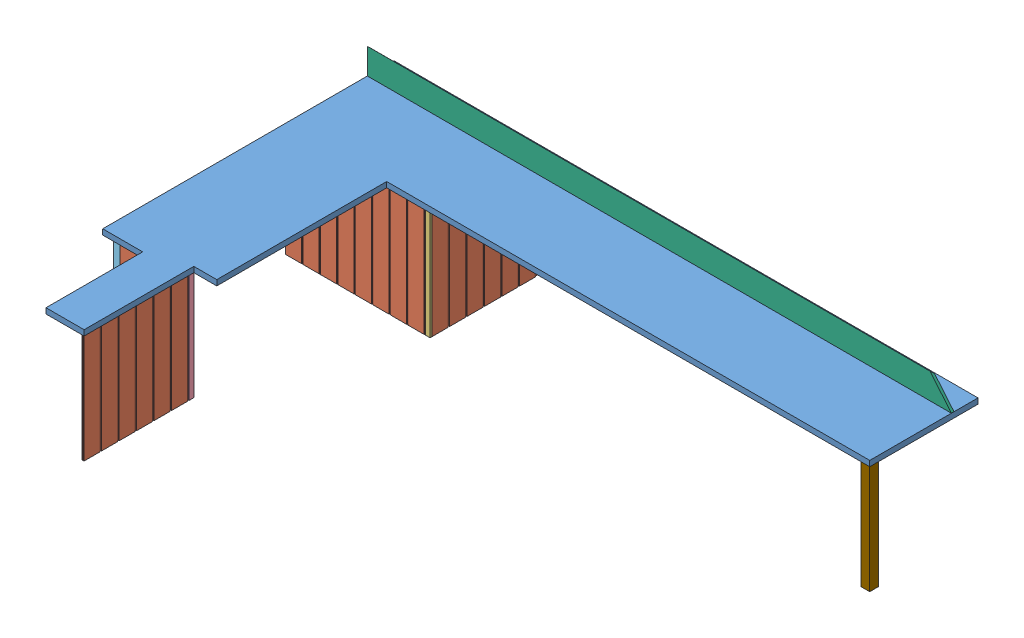
SolidWorks assembly Brüstung-Arbeit, configuration Standard. Lengths in mm.
Overall size (4046.49 966.32 2687.4).
32 component instances, 9 part files, 94 mates.
Components (placement in the parent):
- Werkplatte-1: Werkplatte [Standard] at (-2563.2532 392.3163 2702.7833) size (4046.49 38 2687.4)
- Schalbrett-1: Schalbrett [Standard] at (-2381.7532 392.3163 3445.7833) x (1 0 0) z (0 0 -1) size (131 750 14)
- Schalbrett-2: Schalbrett [Standard] at (-2260.7532 392.3163 3445.7833) x (1 0 0) z (0 0 -1) size (131 750 14)
- Schalbrett-3: Schalbrett [Standard] at (-2139.7532 392.3163 3445.7833) x (1 0 0) z (0 0 -1) size (131 750 14)
- Schalbrett-4: Schalbrett [Standard] at (-2018.7532 392.3163 3445.7833) x (1 0 0) z (0 0 -1) size (131 750 14)
- Schalbrett-5: Schalbrett [Standard] at (-1897.7532 392.3163 3445.7833) x (1 0 0) z (0 0 -1) size (131 750 14)
- Schalbrett-6: Schalbrett [Standard] at (-1776.7532 392.3163 3445.7833) x (1 0 0) z (0 0 -1) size (131 750 14)
- Schalbrett-7: Schalbrett [Standard] at (-1655.7532 392.3163 3445.7833) x (1 0 0) z (0 0 -1) size (131 750 14)
- Schalbrett-15: Schalbrett [Standard] at (-2502.7532 392.3163 3445.7833) x (1 0 0) z (0 0 -1) size (131 750 14)
- Schalbrett-Ecke1-1: Schalbrett-Ecke1 [Standard] at (-1534.7532 392.3163 3445.7833) x (1 0 0) z (0 0 -1) size (32 750 14)
- Schalbrett-9: Schalbrett [Standard] at (-1570.2532 392.3163 3378.2833) x (0 0 -1) z (-1 0 0) size (131 750 14)
- Schalbrett-10: Schalbrett [Standard] at (-1570.2532 392.3163 3257.2833) x (0 0 -1) z (-1 0 0) size (131 750 14)
- Schalbrett-11: Schalbrett [Standard] at (-1570.2532 392.3163 3136.2833) x (0 0 -1) z (-1 0 0) size (131 750 14)
- Schalbrett-12: Schalbrett [Standard] at (-1570.2532 392.3163 3015.2833) x (0 0 -1) z (-1 0 0) size (131 750 14)
- Schalbrett-13: Schalbrett [Standard] at (-1570.2532 392.3163 2894.2833) x (0 0 -1) z (-1 0 0) size (131 750 14)
- Schalbrett-14: Schalbrett [Standard] at (-1570.2532 392.3163 2773.2833) x (0 0 -1) z (-1 0 0) size (131 750 14)
- Schalbrett-16: Schalbrett [Standard] at (-2029.2532 392.3163 5329.6883) x (0 0 -1) z (-1 0 0) size (131 750 14)
- Schalbrett-17: Schalbrett [Standard] at (-2029.2532 392.3163 5208.6883) x (0 0 -1) z (-1 0 0) size (131 750 14)
- Schalbrett-18: Schalbrett [Standard] at (-2029.2532 392.3163 5087.6883) x (0 0 -1) z (-1 0 0) size (131 750 14)
- Schalbrett-19: Schalbrett [Standard] at (-2029.2532 392.3163 4966.6883) x (0 0 -1) z (-1 0 0) size (131 750 14)
- Schalbrett-20: Schalbrett [Standard] at (-2029.2532 392.3163 4845.6883) x (0 0 -1) z (-1 0 0) size (131 750 14)
- Schalbrett-21: Schalbrett [Standard] at (-2029.2532 392.3163 4724.6883) x (0 0 -1) z (-1 0 0) size (131 750 14)
- Schalbrett-23: Schalbrett [Standard] at (-2096.7532 392.3163 4637.1883) x (-1 0 0) z (0 0 1) size (131 750 14)
- Schalbrett-24: Schalbrett [Standard] at (-2217.7532 392.3163 4637.1883) x (-1 0 0) z (0 0 1) size (131 750 14)
- Schalbrett-25: Schalbrett [Standard] at (-2338.7532 392.3163 4637.1883) x (-1 0 0) z (0 0 1) size (131 750 14)
- Schalbrett-26: Schalbrett [Standard] at (-2459.7532 392.3163 4637.1883) x (-1 0 0) z (0 0 1) size (131 750 14)
- Schalbrett-Ecke2-1: Schalbrett-Ecke2 [Standard] at (-2029.2532 392.3163 4603.6883) x (0 0 -1) z (-1 0 0) size (34 750 14)
- Schalbrett-Ecke3-1: Schalbrett-Ecke3 [Standard] at (-2580.7532 392.3163 4637.1883) x (-1 0 0) z (0 0 1) size (43 750 14)
- Steckdosenleiste-1: Steckdosenleiste [Standard] at (-540.0103 519.4748 2868.9113) size (4046.49 178.32 18)
- Tunnel-Unten-1: Tunnel-Unten [Standard] at (-2488.2532 242.3163 4041.4883) x (0 0 -1) z (1 0 0) size (1177.4 18 150)
- Tunnel-Vorn-1: Tunnel-Vorn [Standard] at (-2431.2532 326.3163 4041.4883) x (0 0 -1) z (1 0 0) size (1177.4 132 18)
- Bein-1: Bein [Standard] at (1453.2326 -357.6837 3422.7833) size (60 750 60)
Mates (geometry in assembly coordinates):
- Deckungsgleich1: coincident anti-aligned: plane of Werkplatte-1 through (-2563.2532 392.3163 2702.7833) normal (0 -1 0); plane of Schalbrett-15 through (-2453.2532 392.3163 3448.7833) normal (0 1 0)
- Deckungsgleich2: coincident anti-aligned: plane of Werkplatte-1 through (-2563.2532 392.3163 2702.7833) normal (0 -1 0); plane of Schalbrett-1 through (-2332.2532 392.3163 3448.7833) normal (0 1 0)
- Deckungsgleich3: coincident anti-aligned: plane of Werkplatte-1 through (-2563.2532 392.3163 2702.7833) normal (0 -1 0); plane of Schalbrett-2 through (-2211.2532 392.3163 3448.7833) normal (0 1 0)
- Deckungsgleich4: coincident anti-aligned: plane of Werkplatte-1 through (-2563.2532 392.3163 2702.7833) normal (0 -1 0); plane of Schalbrett-3 through (-2090.2532 392.3163 3448.7833) normal (0 1 0)
- Deckungsgleich5: coincident anti-aligned: plane of Werkplatte-1 through (-2563.2532 392.3163 2702.7833) normal (0 -1 0); plane of Schalbrett-4 through (-1969.2532 392.3163 3448.7833) normal (0 1 0)
- Deckungsgleich6: coincident anti-aligned: plane of Werkplatte-1 through (-2563.2532 392.3163 2702.7833) normal (0 -1 0); plane of Schalbrett-5 through (-1848.2532 392.3163 3448.7833) normal (0 1 0)
- Deckungsgleich7: coincident anti-aligned: plane of Werkplatte-1 through (-2563.2532 392.3163 2702.7833) normal (0 -1 0); plane of Schalbrett-6 through (-1727.2532 392.3163 3448.7833) normal (0 1 0)
- Deckungsgleich8: coincident anti-aligned: plane of Werkplatte-1 through (-2563.2532 392.3163 2702.7833) normal (0 -1 0); plane of Schalbrett-7 through (-1606.2532 392.3163 3448.7833) normal (0 1 0)
- Deckungsgleich10: coincident aligned: plane of Werkplatte-1 through (-2563.2532 430.3163 4630.1883) normal (-1 0 0); plane of Schalbrett-15 through (-2563.2532 -357.6837 3447.7833) normal (-1 0 0)
- Deckungsgleich11: coincident anti-aligned: plane of Schalbrett-1 through (-2432.2532 -357.6837 3447.7833) normal (0 0 -1); plane of Schalbrett-15 through (-2442.2532 -357.6837 3447.7833) normal (0 0 1)
- Deckungsgleich12: coincident anti-aligned: plane of Schalbrett-1 through (-2321.2532 -357.6837 3447.7833) normal (0 0 1); plane of Schalbrett-2 through (-2311.2532 -357.6837 3447.7833) normal (0 0 -1)
- Deckungsgleich13: coincident anti-aligned: plane of Schalbrett-2 through (-2200.2532 -357.6837 3447.7833) normal (0 0 1); plane of Schalbrett-3 through (-2190.2532 -357.6837 3447.7833) normal (0 0 -1)
- Deckungsgleich14: coincident anti-aligned: plane of Schalbrett-3 through (-2079.2532 -357.6837 3447.7833) normal (0 0 1); plane of Schalbrett-4 through (-2069.2532 -357.6837 3447.7833) normal (0 0 -1)
- Deckungsgleich15: coincident anti-aligned: plane of Schalbrett-4 through (-1958.2532 -357.6837 3447.7833) normal (0 0 1); plane of Schalbrett-5 through (-1948.2532 -357.6837 3447.7833) normal (0 0 -1)
- Deckungsgleich16: coincident anti-aligned: plane of Schalbrett-5 through (-1837.2532 -357.6837 3447.7833) normal (0 0 1); plane of Schalbrett-6 through (-1827.2532 -357.6837 3447.7833) normal (0 0 -1)
- Deckungsgleich17: coincident anti-aligned: plane of Schalbrett-6 through (-1716.2532 -357.6837 3447.7833) normal (0 0 1); plane of Schalbrett-7 through (-1706.2532 -357.6837 3447.7833) normal (0 0 -1)
- Deckungsgleich19: coincident aligned: plane of Werkplatte-1 through (-1863.2532 430.3163 3452.7833) normal (0 0 1); plane of Schalbrett-15 through (-2453.2532 -357.6837 3452.7833) normal (0 0 1)
- Deckungsgleich20: coincident anti-aligned: plane of Schalbrett-1 through (-2432.2532 -357.6837 3443.7833) normal (-1 0 0); plane of Schalbrett-15 through (-2432.2532 -357.6837 3447.7833) normal (1 0 0)
- Deckungsgleich21: coincident anti-aligned: plane of Schalbrett-1 through (-2311.2532 -357.6837 3447.7833) normal (1 0 0); plane of Schalbrett-2 through (-2311.2532 -357.6837 3443.7833) normal (-1 0 0)
- Deckungsgleich22: coincident anti-aligned: plane of Schalbrett-2 through (-2190.2532 -357.6837 3447.7833) normal (1 0 0); plane of Schalbrett-3 through (-2190.2532 -357.6837 3443.7833) normal (-1 0 0)
- Deckungsgleich23: coincident anti-aligned: plane of Schalbrett-3 through (-2069.2532 -357.6837 3447.7833) normal (1 0 0); plane of Schalbrett-4 through (-2069.2532 -357.6837 3443.7833) normal (-1 0 0)
- Deckungsgleich24: coincident anti-aligned: plane of Schalbrett-4 through (-1948.2532 -357.6837 3447.7833) normal (1 0 0); plane of Schalbrett-5 through (-1948.2532 -357.6837 3443.7833) normal (-1 0 0)
- Deckungsgleich25: coincident anti-aligned: plane of Schalbrett-5 through (-1827.2532 -357.6837 3447.7833) normal (1 0 0); plane of Schalbrett-6 through (-1827.2532 -357.6837 3443.7833) normal (-1 0 0)
- Deckungsgleich26: coincident anti-aligned: plane of Schalbrett-6 through (-1706.2532 -357.6837 3447.7833) normal (1 0 0); plane of Schalbrett-7 through (-1706.2532 -357.6837 3443.7833) normal (-1 0 0)
- Deckungsgleich28: coincident anti-aligned: plane of Werkplatte-1 through (-2563.2532 392.3163 2702.7833) normal (0 -1 0); plane of Schalbrett-Ecke1-1 through (-1485.2532 392.3163 3448.7833) normal (0 1 0)
- Deckungsgleich29: coincident anti-aligned: plane of Schalbrett-7 through (-1595.2532 -357.6837 3447.7833) normal (0 0 1); plane of Schalbrett-Ecke1-1 through (-1585.2532 -357.6837 3447.7833) normal (0 0 -1)
- Deckungsgleich30: coincident anti-aligned: plane of Schalbrett-7 through (-1585.2532 -357.6837 3447.7833) normal (1 0 0); plane of Schalbrett-Ecke1-1 through (-1585.2532 -357.6837 3443.7833) normal (-1 0 0)
- Deckungsgleich31: coincident anti-aligned: plane of Werkplatte-1 through (-2563.2532 392.3163 2702.7833) normal (0 -1 0); plane of Schalbrett-9 through (-1567.2532 392.3163 3328.7833) normal (0 1 0)
- Deckungsgleich32: coincident anti-aligned: plane of Werkplatte-1 through (-2563.2532 392.3163 2702.7833) normal (0 -1 0); plane of Schalbrett-10 through (-1567.2532 392.3163 3207.7833) normal (0 1 0)
- Deckungsgleich33: coincident anti-aligned: plane of Werkplatte-1 through (-2563.2532 392.3163 2702.7833) normal (0 -1 0); plane of Schalbrett-11 through (-1567.2532 392.3163 3086.7833) normal (0 1 0)
- Deckungsgleich34: coincident anti-aligned: plane of Werkplatte-1 through (-2563.2532 392.3163 2702.7833) normal (0 -1 0); plane of Schalbrett-12 through (-1567.2532 392.3163 2965.7833) normal (0 1 0)
- Deckungsgleich35: coincident anti-aligned: plane of Werkplatte-1 through (-2563.2532 392.3163 2702.7833) normal (0 -1 0); plane of Schalbrett-13 through (-1567.2532 392.3163 2844.7833) normal (0 1 0)
- Deckungsgleich36: coincident anti-aligned: plane of Werkplatte-1 through (-2563.2532 392.3163 2702.7833) normal (0 -1 0); plane of Schalbrett-14 through (-1567.2532 392.3163 2723.7833) normal (0 1 0)
- Deckungsgleich37: coincident anti-aligned: plane of Schalbrett-Ecke1-1 through (-1474.2532 -357.6837 3438.7833) normal (0 0 -1); plane of Schalbrett-9 through (-1568.2532 -357.6837 3438.7833) normal (0 0 1)
- Deckungsgleich38: coincident aligned: plane of Schalbrett-Ecke1-1 through (-1563.2532 642.3163 3438.7833) normal (1 0 0); plane of Schalbrett-9 through (-1563.2532 -357.6837 3328.7833) normal (1 0 0)
- Deckungsgleich39: coincident anti-aligned: plane of Schalbrett-9 through (-1568.2532 -357.6837 3317.7833) normal (1 0 0); plane of Schalbrett-10 through (-1568.2532 -357.6837 3307.7833) normal (-1 0 0)
- Deckungsgleich40: coincident anti-aligned: plane of Schalbrett-10 through (-1568.2532 -357.6837 3196.7833) normal (1 0 0); plane of Schalbrett-11 through (-1568.2532 -357.6837 3186.7833) normal (-1 0 0)
- Deckungsgleich41: coincident anti-aligned: plane of Schalbrett-11 through (-1568.2532 -357.6837 3075.7833) normal (1 0 0); plane of Schalbrett-12 through (-1568.2532 -357.6837 3065.7833) normal (-1 0 0)
- Deckungsgleich42: coincident anti-aligned: plane of Schalbrett-12 through (-1568.2532 -357.6837 2954.7833) normal (1 0 0); plane of Schalbrett-13 through (-1568.2532 -357.6837 2944.7833) normal (-1 0 0)
- Deckungsgleich43: coincident anti-aligned: plane of Schalbrett-13 through (-1568.2532 -357.6837 2833.7833) normal (1 0 0); plane of Schalbrett-14 through (-1568.2532 -357.6837 2823.7833) normal (-1 0 0)
- Deckungsgleich44: coincident anti-aligned: plane of Schalbrett-9 through (-1568.2532 -357.6837 3307.7833) normal (0 0 -1); plane of Schalbrett-10 through (-1572.2532 -357.6837 3307.7833) normal (0 0 1)
- Deckungsgleich45: coincident anti-aligned: plane of Schalbrett-10 through (-1568.2532 -357.6837 3186.7833) normal (0 0 -1); plane of Schalbrett-11 through (-1572.2532 -357.6837 3186.7833) normal (0 0 1)
- Deckungsgleich46: coincident anti-aligned: plane of Schalbrett-11 through (-1568.2532 -357.6837 3065.7833) normal (0 0 -1); plane of Schalbrett-12 through (-1572.2532 -357.6837 3065.7833) normal (0 0 1)
- Deckungsgleich47: coincident anti-aligned: plane of Schalbrett-12 through (-1568.2532 -357.6837 2944.7833) normal (0 0 -1); plane of Schalbrett-13 through (-1572.2532 -357.6837 2944.7833) normal (0 0 1)
- Deckungsgleich48: coincident anti-aligned: plane of Schalbrett-13 through (-1568.2532 -357.6837 2823.7833) normal (0 0 -1); plane of Schalbrett-14 through (-1572.2532 -357.6837 2823.7833) normal (0 0 1)
- Deckungsgleich49: coincident anti-aligned: plane of Werkplatte-1 through (-2563.2532 392.3163 2702.7833) normal (0 -1 0); plane of Schalbrett-16 through (-2026.2532 392.3163 5280.1883) normal (0 1 0)
- Deckungsgleich50: coincident anti-aligned: plane of Werkplatte-1 through (-2563.2532 392.3163 2702.7833) normal (0 -1 0); plane of Schalbrett-17 through (-2026.2532 392.3163 5159.1883) normal (0 1 0)
- Deckungsgleich51: coincident anti-aligned: plane of Werkplatte-1 through (-2563.2532 392.3163 2702.7833) normal (0 -1 0); plane of Schalbrett-18 through (-2026.2532 392.3163 5038.1883) normal (0 1 0)
- Deckungsgleich52: coincident anti-aligned: plane of Werkplatte-1 through (-2563.2532 392.3163 2702.7833) normal (0 -1 0); plane of Schalbrett-19 through (-2026.2532 392.3163 4917.1883) normal (0 1 0)
- Deckungsgleich53: coincident anti-aligned: plane of Werkplatte-1 through (-2563.2532 392.3163 2702.7833) normal (0 -1 0); plane of Schalbrett-20 through (-2026.2532 392.3163 4796.1883) normal (0 1 0)
- Deckungsgleich54: coincident anti-aligned: plane of Werkplatte-1 through (-2563.2532 392.3163 2702.7833) normal (0 -1 0); plane of Schalbrett-21 through (-2026.2532 392.3163 4675.1883) normal (0 1 0)
- Deckungsgleich56: coincident anti-aligned: plane of Werkplatte-1 through (-2563.2532 392.3163 2702.7833) normal (0 -1 0); plane of Schalbrett-23 through (-2146.2532 392.3163 4634.1883) normal (0 1 0)
- Deckungsgleich57: coincident anti-aligned: plane of Werkplatte-1 through (-2563.2532 392.3163 2702.7833) normal (0 -1 0); plane of Schalbrett-24 through (-2267.2532 392.3163 4634.1883) normal (0 1 0)
- Deckungsgleich58: coincident anti-aligned: plane of Werkplatte-1 through (-2563.2532 392.3163 2702.7833) normal (0 -1 0); plane of Schalbrett-25 through (-2388.2532 392.3163 4634.1883) normal (0 1 0)
- Deckungsgleich59: coincident anti-aligned: plane of Werkplatte-1 through (-2563.2532 392.3163 2702.7833) normal (0 -1 0); plane of Schalbrett-26 through (-2509.2532 392.3163 4634.1883) normal (0 1 0)
- Deckungsgleich61: coincident aligned: plane of Werkplatte-1 through (-2022.2532 430.3163 5390.1883) normal (0 0 1); plane of Schalbrett-16 through (-2027.2532 -357.6837 5390.1883) normal (0 0 1)
- Deckungsgleich62: coincident aligned: plane of Werkplatte-1 through (-2022.2532 430.3163 5390.1883) normal (1 0 0); plane of Schalbrett-16 through (-2022.2532 -357.6837 5280.1883) normal (1 0 0)
- Deckungsgleich63: coincident anti-aligned: plane of Schalbrett-16 through (-2027.2532 -357.6837 5269.1883) normal (1 0 0); plane of Schalbrett-17 through (-2027.2532 -357.6837 5259.1883) normal (-1 0 0)
- Deckungsgleich64: coincident anti-aligned: plane of Schalbrett-17 through (-2027.2532 -357.6837 5148.1883) normal (1 0 0); plane of Schalbrett-18 through (-2027.2532 -357.6837 5138.1883) normal (-1 0 0)
- Deckungsgleich65: coincident anti-aligned: plane of Schalbrett-18 through (-2027.2532 -357.6837 5027.1883) normal (1 0 0); plane of Schalbrett-19 through (-2027.2532 -357.6837 5017.1883) normal (-1 0 0)
- Deckungsgleich66: coincident anti-aligned: plane of Schalbrett-19 through (-2027.2532 -357.6837 4906.1883) normal (1 0 0); plane of Schalbrett-20 through (-2027.2532 -357.6837 4896.1883) normal (-1 0 0)
- Deckungsgleich67: coincident anti-aligned: plane of Schalbrett-20 through (-2027.2532 -357.6837 4785.1883) normal (1 0 0); plane of Schalbrett-21 through (-2027.2532 -357.6837 4775.1883) normal (-1 0 0)
- Deckungsgleich69: coincident anti-aligned: plane of Schalbrett-16 through (-2027.2532 -357.6837 5259.1883) normal (0 0 -1); plane of Schalbrett-17 through (-2031.2532 -357.6837 5259.1883) normal (0 0 1)
- Deckungsgleich70: coincident anti-aligned: plane of Schalbrett-17 through (-2027.2532 -357.6837 5138.1883) normal (0 0 -1); plane of Schalbrett-18 through (-2031.2532 -357.6837 5138.1883) normal (0 0 1)
- Deckungsgleich71: coincident anti-aligned: plane of Schalbrett-18 through (-2027.2532 -357.6837 5017.1883) normal (0 0 -1); plane of Schalbrett-19 through (-2031.2532 -357.6837 5017.1883) normal (0 0 1)
- Deckungsgleich72: coincident anti-aligned: plane of Schalbrett-19 through (-2027.2532 -357.6837 4896.1883) normal (0 0 -1); plane of Schalbrett-20 through (-2031.2532 -357.6837 4896.1883) normal (0 0 1)
- Deckungsgleich73: coincident anti-aligned: plane of Schalbrett-20 through (-2027.2532 -357.6837 4775.1883) normal (0 0 -1); plane of Schalbrett-21 through (-2031.2532 -357.6837 4775.1883) normal (0 0 1)
- Deckungsgleich75: coincident anti-aligned: plane of Werkplatte-1 through (-2563.2532 392.3163 2702.7833) normal (0 -1 0); plane of Schalbrett-Ecke2-1 through (-2026.2532 392.3163 4554.1883) normal (0 1 0)
- Deckungsgleich76: coincident anti-aligned: plane of Schalbrett-21 through (-2027.2532 -357.6837 4664.1883) normal (1 0 0); plane of Schalbrett-Ecke2-1 through (-2027.2532 -357.6837 4654.1883) normal (-1 0 0)
- Deckungsgleich77: coincident anti-aligned: plane of Schalbrett-21 through (-2027.2532 -357.6837 4654.1883) normal (0 0 -1); plane of Schalbrett-Ecke2-1 through (-2031.2532 -357.6837 4654.1883) normal (0 0 1)
- Deckungsgleich78: coincident anti-aligned: plane of Werkplatte-1 through (-2563.2532 392.3163 2702.7833) normal (0 -1 0); plane of Schalbrett-23 through (-2146.2532 392.3163 4634.1883) normal (0 1 0)
- Deckungsgleich79: coincident anti-aligned: plane of Schalbrett-23 through (-2036.2532 -357.6837 4644.1883) normal (1 0 0); plane of Schalbrett-Ecke2-1 through (-2036.2532 -357.6837 4543.1883) normal (-1 0 0)
- Deckungsgleich80: coincident aligned: plane of Schalbrett-23 through (-2146.2532 -357.6837 4630.1883) normal (0 0 -1); plane of Schalbrett-Ecke2-1 through (-2022.2532 -607.6837 4630.1883) normal (0 0 -1)
- Deckungsgleich81: coincident anti-aligned: plane of Schalbrett-23 through (-2157.2532 -357.6837 4635.1883) normal (0 0 -1); plane of Schalbrett-24 through (-2167.2532 -357.6837 4635.1883) normal (0 0 1)
- Deckungsgleich82: coincident anti-aligned: plane of Schalbrett-23 through (-2167.2532 -357.6837 4635.1883) normal (-1 0 0); plane of Schalbrett-24 through (-2167.2532 -357.6837 4639.1883) normal (1 0 0)
- Deckungsgleich83: coincident anti-aligned: plane of Schalbrett-24 through (-2278.2532 -357.6837 4635.1883) normal (0 0 -1); plane of Schalbrett-25 through (-2288.2532 -357.6837 4635.1883) normal (0 0 1)
- Deckungsgleich85: coincident anti-aligned: plane of Schalbrett-24 through (-2288.2532 -357.6837 4635.1883) normal (-1 0 0); plane of Schalbrett-25 through (-2288.2532 -357.6837 4639.1883) normal (1 0 0)
- Deckungsgleich86: coincident anti-aligned: plane of Schalbrett-25 through (-2409.2532 -357.6837 4635.1883) normal (-1 0 0); plane of Schalbrett-26 through (-2409.2532 -357.6837 4639.1883) normal (1 0 0)
- Deckungsgleich87: coincident anti-aligned: plane of Schalbrett-25 through (-2399.2532 -357.6837 4635.1883) normal (0 0 -1); plane of Schalbrett-26 through (-2409.2532 -357.6837 4635.1883) normal (0 0 1)
- Deckungsgleich93: coincident anti-aligned: plane of Schalbrett-26 through (-2530.2532 -357.6837 4635.1883) normal (-1 0 0); plane of Schalbrett-Ecke3-1 through (-2530.2532 -357.6837 4639.1883) normal (1 0 0)
- Deckungsgleich94: coincident anti-aligned: plane of Werkplatte-1 through (-2563.2532 392.3163 2702.7833) normal (0 -1 0); plane of Schalbrett-Ecke3-1 through (-2630.2532 392.3163 4634.1883) normal (0 1 0)
- Deckungsgleich96: coincident anti-aligned: plane of Schalbrett-26 through (-2520.2532 -357.6837 4635.1883) normal (0 0 -1); plane of Schalbrett-Ecke3-1 through (-2530.2532 -357.6837 4635.1883) normal (0 0 1)
- Deckungsgleich97: coincident anti-aligned: plane of Werkplatte-1 through (-2563.2532 430.3163 2702.7833) normal (0 1 0); plane of Steckdosenleiste-1 through (-2563.2532 430.3163 2886.9113) normal (0 -1 0)
- Deckungsgleich98: coincident aligned: plane of Werkplatte-1 through (-2563.2532 430.3163 4630.1883) normal (-1 0 0); plane of Steckdosenleiste-1 through (-2563.2532 430.3163 2886.9113) normal (-1 0 0)
- Abstand1: distance = 184.128 mm anti-aligned: plane of Werkplatte-1 through (1483.2326 430.3163 2702.7833) normal (0 0 -1); plane of Steckdosenleiste-1 through (-540.0103 519.4748 2886.9113) normal (0 0 1)
- Deckungsgleich101: coincident aligned: plane of Werkplatte-1 through (-2563.2532 430.3163 4630.1883) normal (-1 0 0); plane of Tunnel-Unten-1 through (-2563.2532 260.3163 4630.1883) normal (-1 0 0)
- Deckungsgleich102: coincident anti-aligned: plane of Schalbrett-26 through (-2509.2532 -357.6837 4630.1883) normal (0 0 -1); plane of Tunnel-Unten-1 through (-2563.2532 260.3163 4630.1883) normal (0 0 1)
- Deckungsgleich103: coincident aligned: plane of Tunnel-Unten-1 through (-2413.2532 260.3163 4630.1883) normal (1 0 0); plane of Tunnel-Vorn-1 through (-2413.2532 326.3163 4041.4883) normal (1 0 0)
- Deckungsgleich104: coincident anti-aligned: plane of Tunnel-Unten-1 through (-2488.2532 260.3163 4041.4883) normal (0 1 0); plane of Tunnel-Vorn-1 through (-2413.2532 260.3163 4630.1883) normal (0 -1 0)
- Deckungsgleich105: coincident anti-aligned: plane of Werkplatte-1 through (-2563.2532 392.3163 2702.7833) normal (0 -1 0); plane of Tunnel-Vorn-1 through (-2413.2532 392.3163 4630.1883) normal (0 1 0)
- Deckungsgleich108: coincident aligned: plane of Tunnel-Unten-1 through (-2563.2532 260.3163 4630.1883) normal (0 0 1); plane of Tunnel-Vorn-1 through (-2413.2532 260.3163 4630.1883) normal (0 0 1)
- Deckungsgleich109: coincident anti-aligned: plane of Werkplatte-1 through (-2563.2532 392.3163 2702.7833) normal (0 -1 0); plane of Bein-1 through (1453.2326 392.3163 3422.7833) normal (0 1 0)
- Deckungsgleich110: coincident aligned: plane of Werkplatte-1 through (1483.2326 430.3163 3452.7833) normal (1 0 0); plane of Bein-1 through (1483.2326 392.3163 3452.7833) normal (1 0 0)
- Deckungsgleich111: coincident aligned: plane of Werkplatte-1 through (-1863.2532 430.3163 3452.7833) normal (0 0 1); plane of Bein-1 through (1423.2326 392.3163 3452.7833) normal (0 0 1)
